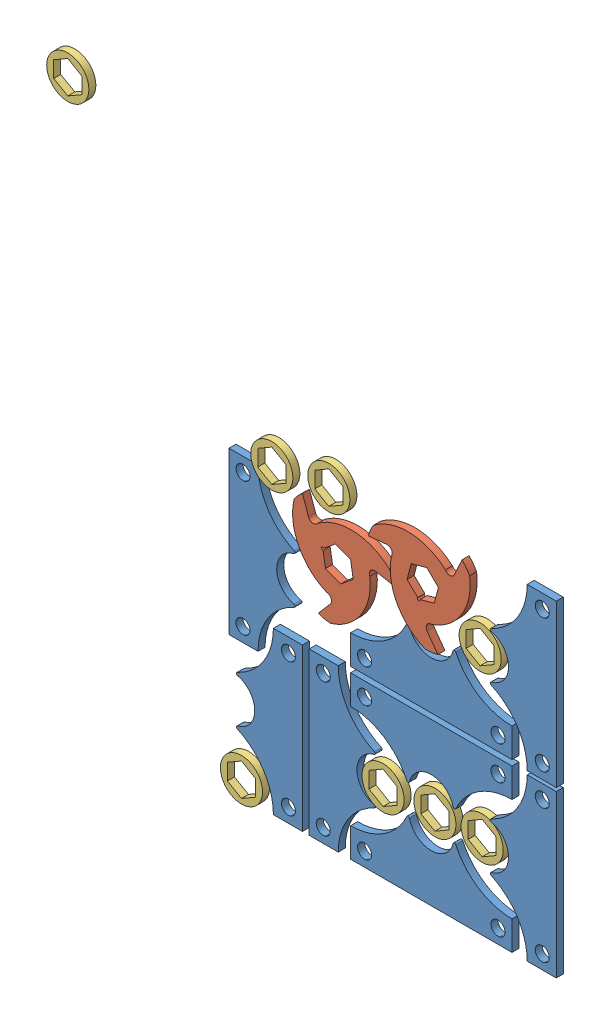
SolidWorks assembly Flat_Pattern_4, configuration Default. Lengths in mm.
Overall size (463.95 508.23 15.87).
18 component instances, 3 part files, 18 mates.
Components (placement in the parent):
- Spacer_2-1: Spacer_2 [Default] at origin size (59.73 146.05 6.35)
- Spacer_2-2: Spacer_2 [Default] at (-94.0242 -53.975 0) x (0 -1 0) z (0 0 1) size (59.73 146.05 6.35)
- Spacer_2-3: Spacer_2 [Default] at (-185.4426 0 0) x (-1 0 0) z (0 0 1) size (59.73 146.05 6.35)
- Spacer_2-4: Spacer_2 [Default] at (-94.0242 53.975 0) x (0 1 0) z (0 0 1) size (59.73 146.05 6.35)
- Spacer_2-5: Spacer_2 [Default] at (-258.0211 121.0119 0) x (-1 0 0) z (0 0 1) size (59.73 146.05 6.35)
- Spacer_2-6: Spacer_2 [Default] at (0 149.2038 0) size (59.73 146.05 6.35)
- Spacer_2-7: Spacer_2 [Default] at (-94.0242 97.1279 0) x (0 -1 0) z (0 0 1) size (59.73 146.05 6.35)
- Spacer_2-8: Spacer_2 [Default] at (-229.6193 0 0) size (59.73 146.05 6.35)
- Cutter_3-1: Cutter_3 [Default] at (-95.3871 182.0877 6.35) x (-0.963081 -0.26921 0) z (-0.26921 0.963081 0) size (280.09 6.35 281.96)
- Cutter_3-2: Cutter_3 [Default] at (-178.387 152.6245 0) x (-0.773457 -0.633848 0) z (0.633848 -0.773457 0) size (280.09 6.35 281.96)
- Hex_Spacer-1: Hex_Spacer [Default] at (-93.9192 -1.4115 -3.175) size (38.1 38.1 6.35)
- Hex_Spacer-2: Hex_Spacer [Default] at (-262.5718 -56.9086 3.175) size (38.1 38.1 6.35)
- Hex_Spacer-3: Hex_Spacer [Default] at (-189.8921 205.1246 -3.175) size (38.1 38.1 6.35)
- Hex_Spacer-4: Hex_Spacer [Default] at (-422.8937 411.7487 0) size (38.1 38.1 6.35)
- Hex_Spacer-5: Hex_Spacer [Default] at (-231.9679 205.9454 6.35) size (38.1 38.1 6.35)
- Hex_Spacer-6: Hex_Spacer [Default] at (-134.5086 0.7851 3.175) size (38.1 38.1 6.35)
- Hex_Spacer-7: Hex_Spacer [Default] at (-51.1732 -0.111 -3.175) size (38.1 38.1 6.35)
- Hex_Spacer-8: Hex_Spacer [Default] at (-52.9654 148.6382 -3.175) size (38.1 38.1 6.35)
Mates (geometry in assembly coordinates):
- Coincident1: coincident: line of Spacer_2-1 through (-7.2461 -73.025 3.175) axis (1 0 0); line of Spacer_2-2 through (-167.0492 -73.025 3.175) axis (1 0 0)
- Coincident2: coincident: plane of Spacer_2-1 through (0 0 3.175) normal (0 0 1); plane of Spacer_2-2 through (-94.0242 -53.975 3.175) normal (0 0 1)
- Coincident4: coincident: line of Spacer_2-1 through (-7.2461 73.025 3.175) axis (1 0 0); line of Spacer_2-4 through (-20.9992 73.025 3.175) axis (-1 0 0)
- Coincident5: coincident: line of Spacer_2-2 through (-167.0492 -46.7289 3.175) axis (0 -1 0); line of Spacer_2-4 through (-167.0492 46.7289 3.175) axis (0 1 0)
- Coincident6: coincident: plane of Spacer_2-1 through (0 0 3.175) normal (0 0 1); plane of Spacer_2-3 through (-185.4426 0 3.175) normal (0 0 1)
- Coincident7: coincident: plane of Spacer_2-1 through (0 0 3.175) normal (0 0 1); plane of Spacer_2-4 through (-94.0242 53.975 3.175) normal (0 0 1)
- Parallel1: parallel: line of Spacer_2-3 through (-204.4926 73.025 3.175) axis (0 -1 0); line of assembly
- Coincident9: coincident: line of Spacer_2-1 through (-7.2461 -73.025 3.175) axis (1 0 0); line of Spacer_2-3 through (-178.1965 -73.025 3.175) axis (-1 0 0)
- Coincident10: coincident: plane of Spacer_2-1 through (0 0 3.175) normal (0 0 1); plane of Spacer_2-8 through (-229.6193 0 3.175) normal (0 0 1)
- Coincident11: coincident: line of Spacer_2-3 through (-178.1965 -73.025 3.175) axis (-1 0 0); line of Spacer_2-8 through (-236.8655 -73.025 3.175) axis (1 0 0)
- Coincident12: coincident: plane of Spacer_2-1 through (0 0 3.175) normal (0 0 1); plane of Spacer_2-5 through (-258.0211 121.0119 3.175) normal (0 0 1)
- Parallel2: parallel: line of Spacer_2-5 through (-277.0711 194.0369 3.175) axis (0 -1 0); line of assembly
- Coincident14: coincident: plane of Spacer_2-1 through (0 0 3.175) normal (0 0 1); plane of Spacer_2-7 through (-94.0242 97.1279 3.175) normal (0 0 1)
- Parallel3: parallel: line of Spacer_2-4 through (-20.9992 73.025 3.175) axis (-1 0 0); line of Spacer_2-7 through (-167.0492 78.0779 3.175) axis (1 0 0)
- Coincident17: coincident: line of Spacer_2-1 through (19.05 -73.025 3.175) axis (0 1 0); line of Spacer_2-6 through (19.05 76.1788 3.175) axis (0 1 0)
- Coincident18: coincident: line of Spacer_2-4 through (-20.9992 46.7289 3.175) axis (0 1 0); line of Spacer_2-7 through (-20.9992 104.374 3.175) axis (0 -1 0)
- Coincident20: coincident: plane of Spacer_2-1 through (0 0 3.175) normal (0 0 1); plane of Cutter_3-1 through (-95.3871 182.0877 3.175) normal (0 0 -1)
- Coincident21: coincident: plane of Spacer_2-1 through (0 0 3.175) normal (0 0 1); plane of Cutter_3-2 through (-178.387 152.6245 3.175) normal (0 0 1)
